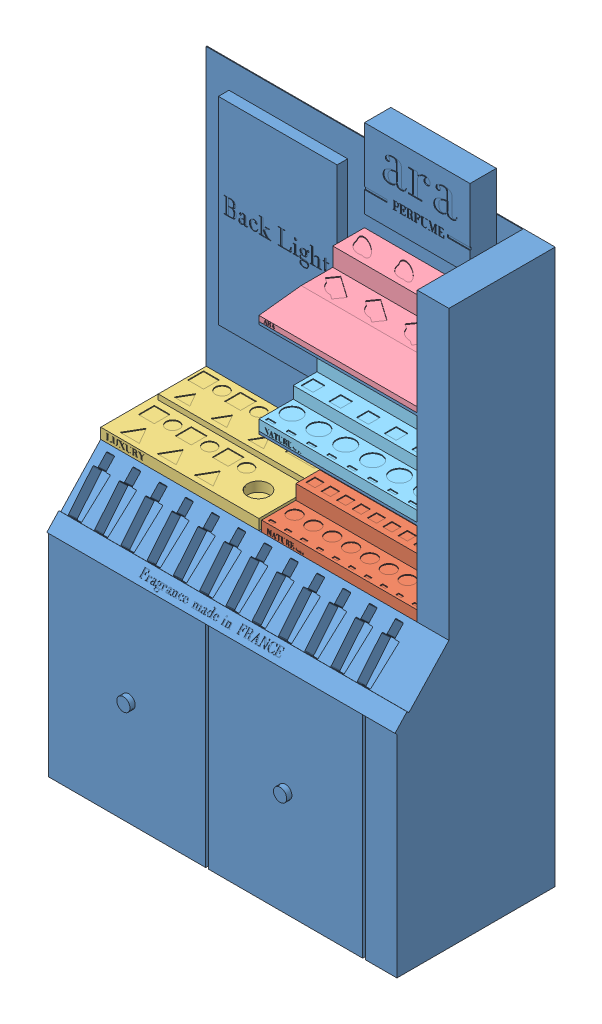
SolidWorks assembly Assem1, configuration Default. Lengths in mm.
Overall size (1320 2250 620).
5 component instances, 5 part files, 11 mates.
Components (placement in the parent):
- Part1-1: Part1 [Default] at (1012.9867 872.3575 2357.4401) x (-1 0 0) z (0 0 -1) size (1320 2250 620)
- stand_new_nature_30ml-1: stand_new_nature_30ml [Default] at (1612.9867 1522.3575 2160.4401) size (590 150 400)
- stand_new_luxury-1: stand_new_luxury [Default] at (712.9867 1522.3575 1960.4401) size (600 60 400)
- stand_ara-1: stand_ara [Default] at (1012.9867 2169.3575 2160.4401) size (600 107.87 400)
- stand_new_nature_100ml-1: stand_new_nature_100ml [Default] at (1612.9867 1849.3575 2160.4401) size (600 175 400)
Mates (geometry in assembly coordinates):
- Coincident1: coincident anti-aligned: plane of Part1-1 through (1612.9867 1482.3575 2160.4401) normal (0 1 0); plane of stand_new_nature_30ml-1 through (1022.9867 1482.3575 1760.4401) normal (0 -1 0)
- Coincident2: coincident anti-aligned: line of Part1-1 through (1612.9867 1482.3575 2160.4401) axis (-1 0 0); line of stand_new_nature_30ml-1 through (1022.9867 1482.3575 2160.4401) axis (1 0 0)
- Coincident3: coincident anti-aligned: plane of Part1-1 through (1612.9867 472.3575 2160.4401) normal (-1 0 0); plane of stand_new_nature_30ml-1 through (1612.9867 1522.3575 2160.4401) normal (1 0 0)
- Coincident4: coincident anti-aligned: line of Part1-1 through (1612.9867 1482.3575 2160.4401) axis (-1 0 0); line of stand_new_luxury-1 through (412.9867 1482.3575 2160.4401) axis (1 0 0)
- Coincident6: coincident: point of Part1-1; point of stand_new_luxury-1
- Coincident7: coincident anti-aligned: plane of Part1-1 through (1612.9867 2169.3575 2760.5234) normal (0 1 0); plane of stand_ara-1 through (1612.9867 2169.3575 2160.4401) normal (0 -1 0)
- Coincident9: coincident anti-aligned: plane of Part1-1 through (1612.9867 472.3575 2160.4401) normal (-1 0 0); plane of stand_ara-1 through (1612.9867 2169.3575 2160.4401) normal (1 0 0)
- Coincident10: coincident anti-aligned: plane of Part1-1 through (1012.9867 872.3575 1760.4401) normal (0 0 1); plane of stand_ara-1 through (1612.9867 2169.3575 1760.4401) normal (0 0 -1)
- Coincident11: coincident anti-aligned: plane of Part1-1 through (1612.9867 1809.3575 2160.4401) normal (0 1 0); plane of stand_new_nature_100ml-1 through (1012.9867 1809.3575 1760.4401) normal (0 -1 0)
- Coincident12: coincident anti-aligned: plane of Part1-1 through (1612.9867 472.3575 2160.4401) normal (-1 0 0); plane of stand_new_nature_100ml-1 through (1612.9867 1849.3575 2160.4401) normal (1 0 0)
- Coincident13: coincident anti-aligned: plane of Part1-1 through (1012.9867 872.3575 1760.4401) normal (0 0 1); plane of stand_new_nature_100ml-1 through (1012.9867 1894.3575 1760.4401) normal (0 0 -1)
